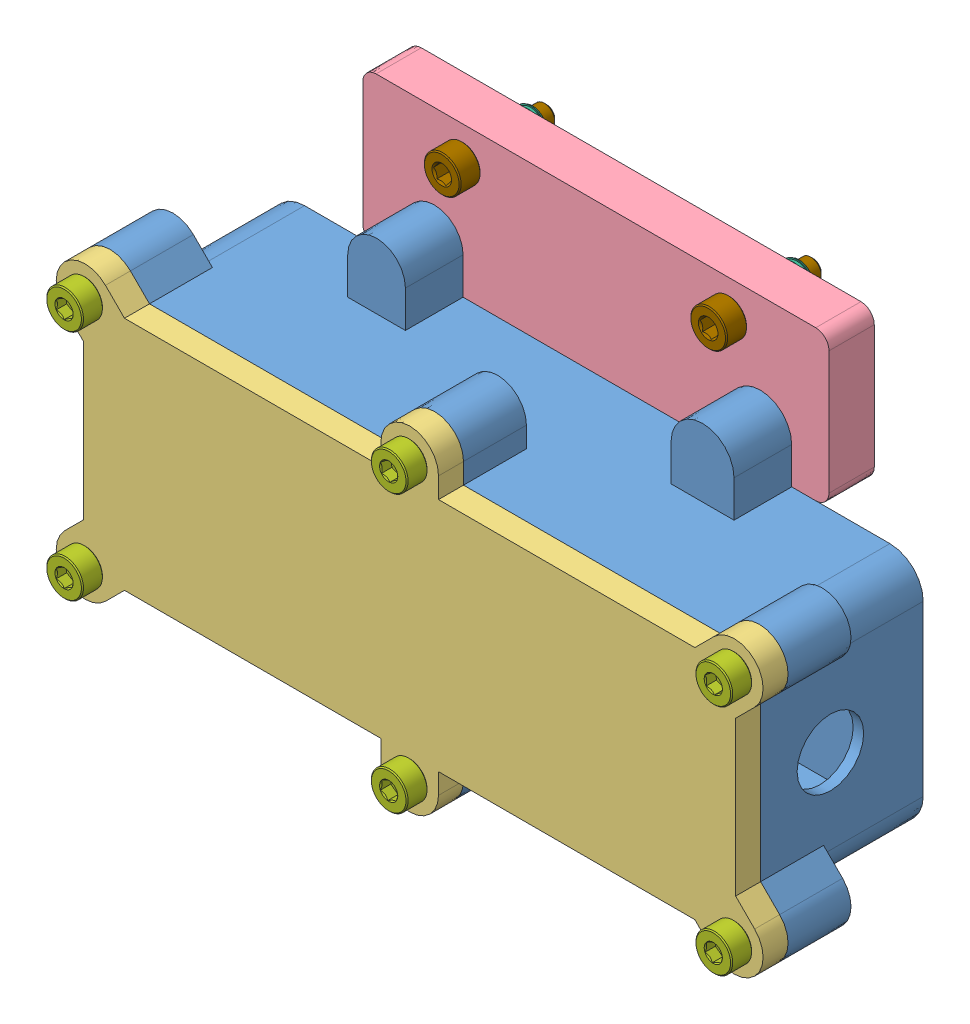
SolidWorks assembly EL-A0107-AA-HVI Assembly, configuration Default. Lengths in mm.
Overall size (134.78 82.91 55.94).
30 component instances, 9 part files, 50 mates.
Components (placement in the parent):
- EL-50090-AA-HVI Enclosure-1: EL-50090-AA-HVI Enclosure [Default] at (62.15 22.4625 5) size (134.78 67.33 31)
- EL-80091-AA-HVI PCB-1: EL-80091-AA-HVI PCB [Default] at (128.7615 -37.799 12.4115) x (0 1 0) z (0 0 1) size (31.42 97.92 12)
- EL-60092-AA-HVI Enclosure Lid-1: EL-60092-AA-HVI Enclosure Lid [Default] at (-49.5888 88.2769 31) size (134.78 63.74 4.76)
- EL-50093-AA-HVI Mounting Adapter-1: EL-50093-AA-HVI Mounting Adapter [Default] at (0 44.925 0) size (88.9 28.57 8.62)
- AC-Heat Set Insert, M4x7-4.7 (94180A351)-1: AC-Heat Set Insert, M4x7-4.7 (94180A351) [94180A351] at (0.2622 0.2622 28.65) size (6.35 6.35 4.7)
- AC-Heat Set Insert, M4x7-4.7 (94180A351)-5: AC-Heat Set Insert, M4x7-4.7 (94180A351) [94180A351] at (62.15 -3.9097 28.65) x (-0.587416 -0.809285 0) z (0 0 1) size (6.35 6.35 4.7)
- AC-Heat Set Insert, M4x7-4.7 (94180A351)-7: AC-Heat Set Insert, M4x7-4.7 (94180A351) [94180A351] at (124.0378 0.2622 28.65) x (-0.503998 -0.863705 0) z (0 0 1) size (6.35 6.35 4.7)
- FS-Heat Set Insert, M4x7-4.7 (94180A351)-7: FS-Heat Set Insert, M4x7-4.7 (94180A351) [94180A351] at (93.225 51.925 2.35) x (-0.503998 0.863705 0) z (0 0 -1) size (6.35 6.35 4.7)
- BR-Black Oxide C12.9 SHCS, M4x0.7-8 (91290A140)-7: BR-Black Oxide C12.9 SHCS, M4x0.7-8 (91290A140) [91290A140] at (93.225 51.925 -1.62) x (0.720828 -0.693114 0) z (0 0 -1) size (7 7 12.17)
- FS-Heat Set Insert, M4x7-4.7 (94180A351)-11: FS-Heat Set Insert, M4x7-4.7 (94180A351) [94180A351] at (17.6365 32.94 9.65) size (6.35 6.35 4.7)
- FS-Heat Set Insert, M4x7-4.7 (94180A351)-12: FS-Heat Set Insert, M4x7-4.7 (94180A351) [94180A351] at (17.6365 11.985 9.65) size (6.35 6.35 4.7)
- FS-Heat Set Insert, M4x7-4.7 (94180A351)-13: FS-Heat Set Insert, M4x7-4.7 (94180A351) [94180A351] at (106.2765 22.365 9.65) size (6.35 6.35 4.7)
- BR-Black Oxide C12.9 SHCS, M4x0.7-5 (91290A138)-1: BR-Black Oxide C12.9 SHCS, M4x0.7-5 (91290A138) [91290A138] at (17.6365 32.94 11.9115) x (-0.76758 0.640953 0) z (0 0 1) size (7 7 9.17)
- BR-Black Oxide C12.9 SHCS, M4x0.7-5 (91290A138)-2: BR-Black Oxide C12.9 SHCS, M4x0.7-5 (91290A138) [91290A138] at (17.6365 11.985 11.9115) x (0.49038 0.871509 0) z (0 0 1) size (7 7 9.17)
- BR-Black Oxide C12.9 SHCS, M4x0.7-5 (91290A138)-3: BR-Black Oxide C12.9 SHCS, M4x0.7-5 (91290A138) [91290A138] at (106.2765 22.365 11.9115) x (-0.851115 -0.52498 0) z (0 0 1) size (7 7 9.17) (hidden)
- 91290A154_Alloy Steel Socket Head Screw, M4x0.7, 16mm-1: 91290A154_Alloy Steel Socket Head Screw, M4x0.7, 16mm [91290A154] at (36.5 67.15 -6) x (0.781191 -0.624293 0) z (0 0 1) size (7 7 20.04)
- 91290A154_Alloy Steel Socket Head Screw, M4x0.7, 16mm-2: 91290A154_Alloy Steel Socket Head Screw, M4x0.7, 16mm [91290A154] at (87.3 67.15 -6) x (0.964834 0.262859 0) z (0 0 1) size (7 7 20.04)
- FS-Heat Set Insert, M4x7-4.7 (94180A351)-14: FS-Heat Set Insert, M4x7-4.7 (94180A351) [94180A351] at (36.5 67.15 -10.97) x (-0.244903 0.969548 0) z (0 0 1) size (6.35 6.35 4.7)
- FS-Heat Set Insert, M4x7-4.7 (94180A351)-15: FS-Heat Set Insert, M4x7-4.7 (94180A351) [94180A351] at (87.3 67.15 -10.97) x (0.839545 -0.543291 0) z (0 0 1) size (6.35 6.35 4.7)
- BR-Black Oxide C12.9 SHCS, M4x0.7-8 (91290A140)-9: BR-Black Oxide C12.9 SHCS, M4x0.7-8 (91290A140) [91290A140] at (0.2622 0.2622 33.7625) size (7 7 12.17)
- BR-Black Oxide C12.9 SHCS, M4x0.7-8 (91290A140)-10: BR-Black Oxide C12.9 SHCS, M4x0.7-8 (91290A140) [91290A140] at (62.15 -3.9097 33.7625) x (-0.596658 -0.802496 0) z (0 0 1) size (7 7 12.17)
- BR-Black Oxide C12.9 SHCS, M4x0.7-8 (91290A140)-11: BR-Black Oxide C12.9 SHCS, M4x0.7-8 (91290A140) [91290A140] at (124.0378 0.2622 33.7625) x (-0.596658 -0.802496 0) z (0 0 1) size (7 7 12.17)
- AC-Heat Set Insert, M4x7-4.7 (94180A351)-4: AC-Heat Set Insert, M4x7-4.7 (94180A351) [94180A351] at (0.2622 44.6628 28.65) x (1 0 0) z (0 0 -1) size (6.35 6.35 4.7)
- AC-Heat Set Insert, M4x7-4.7 (94180A351)-6: AC-Heat Set Insert, M4x7-4.7 (94180A351) [94180A351] at (62.15 48.8347 28.65) x (-0.587416 0.809285 0) z (0 0 -1) size (6.35 6.35 4.7)
- AC-Heat Set Insert, M4x7-4.7 (94180A351)-8: AC-Heat Set Insert, M4x7-4.7 (94180A351) [94180A351] at (124.0378 44.6628 28.65) x (-0.503998 0.863705 0) z (0 0 -1) size (6.35 6.35 4.7)
- BR-Black Oxide C12.9 SHCS, M4x0.7-8 (91290A140)-8: BR-Black Oxide C12.9 SHCS, M4x0.7-8 (91290A140) [91290A140] at (31.075 51.925 -1.62) x (0.720828 -0.693114 0) z (0 0 -1) size (7 7 12.17)
- FS-Heat Set Insert, M4x7-4.7 (94180A351)-9: FS-Heat Set Insert, M4x7-4.7 (94180A351) [94180A351] at (31.075 51.925 2.35) x (-0.503998 0.863705 0) z (0 0 -1) size (6.35 6.35 4.7) (suppressed, hidden)
- BR-Black Oxide C12.9 SHCS, M4x0.7-8 (91290A140)-12: BR-Black Oxide C12.9 SHCS, M4x0.7-8 (91290A140) [91290A140] at (0.2622 44.6628 33.7625) x (-1 0 0) z (0 0 1) size (7 7 12.17)
- BR-Black Oxide C12.9 SHCS, M4x0.7-8 (91290A140)-13: BR-Black Oxide C12.9 SHCS, M4x0.7-8 (91290A140) [91290A140] at (62.15 48.8347 33.7625) x (0.596658 -0.802496 0) z (0 0 1) size (7 7 12.17)
- BR-Black Oxide C12.9 SHCS, M4x0.7-8 (91290A140)-14: BR-Black Oxide C12.9 SHCS, M4x0.7-8 (91290A140) [91290A140] at (124.0378 44.6628 33.7625) x (0.596658 -0.802496 0) z (0 0 1) size (7 7 12.17)
Mates (geometry in assembly coordinates):
- Coincident1: coincident anti-aligned: plane of EL-500XX-AA-HVI Enclosure-1 through (62.15 22.4625 0) normal (0 0 -1)
- Coincident2: coincident anti-aligned: plane of EL-500XX-AA-HVI Enclosure-1 through (5 0 31) normal (0 -1 0)
- Coincident3: coincident anti-aligned: plane of EL-500XX-AA-HVI Enclosure-1 through (0 39.925 31) normal (-1 0 0)
- Width3: width aligned: plane of EL-500XX-AA-HVI Enclosure-1 through (5 39.925 31) normal (0 -1 0); plane of EL-800XX-BA-HVI Board-1 through (5 5 31) normal (0 1 0); plane of EL-500XX-AA-HVI Enclosure-1 through (13.1915 8.302 12) normal (0 -1 0); plane of EL-800XX-BA-HVI Board-1 through (111.1085 36.623 12) normal (0 1 0)
- Coincident5: coincident anti-aligned: plane of EL-500XX-AA-HVI Enclosure-1 through (17.6365 11.985 12) normal (0 0 1); plane of EL-800XX-BA-HVI Board-1 through (62.15 22.4625 12) normal (0 0 -1)
- Width4: width aligned: plane of EL-800XX-BA-HVI Board-1 through (111.1085 8.302 12) normal (1 0 0); plane of EL-500XX-AA-HVI Enclosure-1 through (13.1915 36.623 12) normal (-1 0 0); plane of EL-800XX-BA-HVI Board-1 through (5 39.925 31) normal (1 0 0); plane of EL-500XX-AA-HVI Enclosure-1 through (119.3 39.925 31) normal (-1 0 0)
- Coincident6: coincident aligned: plane of EL-500XX-AA-HVI Enclosure-1 through (62.15 22.4625 31) normal (0 0 1); plane of EL-60092-AA-HVI Enclosure Lid-1 through (-49.5888 88.2769 31) normal (0 0 1)
- Concentric2: concentric anti-aligned: cylinder of EL-500XX-AA-HVI Enclosure-1 through (31.075 51.925 9) axis (0 0 -1) radius 3.025; cylinder of EL-300XX-AA-HVI Enclosure Tab-2 through (31.075 51.925 0) axis (0 0 1) radius 2.25
- Coincident10: coincident anti-aligned: plane of EL-500XX-AA-HVI Enclosure-1 through (62.15 22.4625 0) normal (0 0 -1); plane of EL-300XX-AA-HVI Enclosure Tab-2 through (31.075 51.925 0) normal (0 0 1)
- Concentric4: concentric aligned: cylinder of EL-500XX-AA-HVI Enclosure-1 through (0.2622 0.2622 22) axis (0 0 1) radius 3.025; cylinder of FS-Heat Set Insert, M4x7-4.7 (94180A351)-1 through (0.2622 0.2622 31) axis (0 0 1) radius 2
- Coincident15: coincident aligned: plane of EL-500XX-AA-HVI Enclosure-1 through (62.15 22.4625 31) normal (0 0 1); plane of FS-Heat Set Insert, M4x7-4.7 (94180A351)-1 through (0.2622 2.2622 31) normal (0 0 1)
- Concentric6: concentric aligned: cylinder of EL-500XX-AA-HVI Enclosure-1 through (62.15 -3.9097 22) axis (0 0 1) radius 3.025; cylinder of AC-Heat Set Insert, M4x7-4.7 (94180A351)-5 through (62.15 -3.9097 31) axis (0 0 1) radius 2
- Coincident16: coincident aligned: plane of EL-500XX-AA-HVI Enclosure-1 through (62.15 22.4625 31) normal (0 0 1); plane of AC-Heat Set Insert, M4x7-4.7 (94180A351)-5 through (63.7686 -5.0845 31) normal (0 0 1)
- Concentric7: concentric aligned: cylinder of EL-500XX-AA-HVI Enclosure-1 through (124.0378 0.2622 22) axis (0 0 1) radius 3.025; cylinder of FS-Heat Set Insert, M4x7-4.7 (94180A351)-3 through (124.0378 0.2622 31) axis (0 0 1) radius 2
- Coincident17: coincident aligned: plane of EL-500XX-AA-HVI Enclosure-1 through (62.15 22.4625 31) normal (0 0 1); plane of FS-Heat Set Insert, M4x7-4.7 (94180A351)-3 through (125.7652 -0.7458 31) normal (0 0 1)
- Concentric16: concentric aligned: cylinder of EL-500XX-AA-HVI Enclosure-1 through (93.225 51.925 9) axis (0 0 -1) radius 3.025; cylinder of FS-Heat Set Insert, M4x7-4.7 (94180A351)-7 through (93.225 51.925 0) axis (0 0 -1) radius 2
- Coincident21: coincident aligned: plane of EL-500XX-AA-HVI Enclosure-1 through (62.15 22.4625 0) normal (0 0 -1); plane of FS-Heat Set Insert, M4x7-4.7 (94180A351)-7 through (94.9524 52.933 0) normal (0 0 -1)
- Concentric17: concentric anti-aligned: cylinder of FS-Heat Set Insert, M4x7-4.7 (94180A351)-7 through (93.225 51.925 0) axis (0 0 -1) radius 2; cylinder of BR-Black Oxide C12.9 SHCS, M4x0.7-8 (91290A140)-7 through (93.225 51.925 4.38) axis (0 0 1) radius 2
- Concentric19: concentric anti-aligned: cylinder of EL-500XX-AA-HVI Enclosure-1 through (17.6365 32.94 12) axis (0 0 -1) radius 3.025; cylinder of FS-Heat Set Insert, M4x7-4.7 (94180A351)-11 through (17.6365 32.94 12) axis (0 0 1) radius 2
- Coincident25: coincident aligned: plane of EL-500XX-AA-HVI Enclosure-1 through (17.6365 32.94 12) normal (0 0 1); plane of FS-Heat Set Insert, M4x7-4.7 (94180A351)-11 through (17.6365 34.94 12) normal (0 0 1)
- Concentric21: concentric anti-aligned: cylinder of EL-500XX-AA-HVI Enclosure-1 through (17.6365 11.985 12) axis (0 0 -1) radius 3.025; cylinder of FS-Heat Set Insert, M4x7-4.7 (94180A351)-12 through (17.6365 11.985 12) axis (0 0 1) radius 2
- Coincident26: coincident aligned: plane of EL-500XX-AA-HVI Enclosure-1 through (17.6365 11.985 12) normal (0 0 1); plane of FS-Heat Set Insert, M4x7-4.7 (94180A351)-12 through (17.6365 13.985 12) normal (0 0 1)
- Concentric22: concentric anti-aligned: cylinder of EL-500XX-AA-HVI Enclosure-1 through (106.2765 22.365 12) axis (0 0 -1) radius 3.025; cylinder of FS-Heat Set Insert, M4x7-4.7 (94180A351)-13 through (106.2765 22.365 12) axis (0 0 1) radius 2
- Coincident28: coincident aligned: plane of EL-500XX-AA-HVI Enclosure-1 through (106.2765 22.365 12) normal (0 0 1); plane of FS-Heat Set Insert, M4x7-4.7 (94180A351)-13 through (106.2765 24.365 12) normal (0 0 1)
- Concentric23: concentric anti-aligned: cylinder of FS-Heat Set Insert, M4x7-4.7 (94180A351)-11 through (17.6365 32.94 12) axis (0 0 1) radius 2; cylinder of BR-Black Oxide C12.9 SHCS, M4x0.7-5 (91290A138)-1 through (17.6365 32.94 7.4115) axis (0 0 -1) radius 2
- Coincident29: coincident anti-aligned: plane of EL-800XX-BA-HVI Board-1 through (62.15 22.4625 12.4115) normal (0 0 1); plane of BR-Black Oxide C12.9 SHCS, M4x0.7-5 (91290A138)-1 through (15.5214 30.407 12.4115) normal (0 0 -1)
- Concentric25: concentric anti-aligned: cylinder of FS-Heat Set Insert, M4x7-4.7 (94180A351)-12 through (17.6365 11.985 12) axis (0 0 1) radius 2; cylinder of BR-Black Oxide C12.9 SHCS, M4x0.7-5 (91290A138)-2 through (17.6365 11.985 7.4115) axis (0 0 -1) radius 2
- Coincident30: coincident anti-aligned: plane of EL-800XX-BA-HVI Board-1 through (62.15 22.4625 12.4115) normal (0 0 1); plane of BR-Black Oxide C12.9 SHCS, M4x0.7-5 (91290A138)-2 through (14.7605 13.6033 12.4115) normal (0 0 -1)
- Concentric26: concentric anti-aligned: cylinder of FS-Heat Set Insert, M4x7-4.7 (94180A351)-13 through (106.2765 22.365 12) axis (0 0 1) radius 2; cylinder of BR-Black Oxide C12.9 SHCS, M4x0.7-5 (91290A138)-3 through (106.2765 22.365 7.4115) axis (0 0 -1) radius 2
- Coincident32: coincident anti-aligned: plane of EL-800XX-BA-HVI Board-1 through (62.15 22.4625 12.4115) normal (0 0 1); plane of BR-Black Oxide C12.9 SHCS, M4x0.7-5 (91290A138)-3 through (108.0089 19.5563 12.4115) normal (0 0 -1)
- Coincident33: coincident anti-aligned: plane of EL-500XX-AA-HVI Enclosure-1 through (62.15 22.4625 0) normal (0 0 -1); plane of EL-50093-AA-HVI Mounting Adapter-1 through (0 44.925 0) normal (0 0 1)
- Coincident34: coincident aligned: plane of EL-500XX-AA-HVI Enclosure-1 through (5 44.925 31) normal (0 1 0); plane of EL-50093-AA-HVI Mounting Adapter-1 through (0 44.925 0) normal (0 1 0)
- Coincident35: coincident anti-aligned: plane of EL-500XX-AA-HVI Enclosure-1 through (0 39.925 31) normal (-1 0 0); plane of EL-50093-AA-HVI Mounting Adapter-1 through (0 44.925 0) normal (1 0 0)
- Coincident36: coincident anti-aligned: plane of EL-50093-AA-HVI Mounting Adapter-1 through (95.475 51.925 -3.62) normal (0 0 -1); plane of BR-Black Oxide C12.9 SHCS, M4x0.7-8 (91290A140)-7 through (90.9377 49.5463 -3.62) normal (0 0 1)
- Concentric28: concentric anti-aligned: cylinder of EL-50093-AA-HVI Mounting Adapter-1 through (36.5 67.15 0) axis (0 0 1) radius 2.25; cylinder of 91290A154_Alloy Steel Socket Head Screw, M4x0.7, 16mm-1 through (36.5 67.15 -16) axis (0 0 -1) radius 2
- Concentric29: concentric anti-aligned: cylinder of EL-50093-AA-HVI Mounting Adapter-1 through (87.3 67.15 0) axis (0 0 1) radius 2.25; cylinder of 91290A154_Alloy Steel Socket Head Screw, M4x0.7, 16mm-2 through (87.3 67.15 -16) axis (0 0 -1) radius 2
- Coincident37: coincident anti-aligned: plane of EL-50093-AA-HVI Mounting Adapter-1 through (0 44.925 0) normal (0 0 1); plane of 91290A154_Alloy Steel Socket Head Screw, M4x0.7, 16mm-1 through (38.5602 69.7279 0) normal (0 0 -1)
- Coincident38: coincident anti-aligned: plane of EL-50093-AA-HVI Mounting Adapter-1 through (0 44.925 0) normal (0 0 1); plane of 91290A154_Alloy Steel Socket Head Screw, M4x0.7, 16mm-2 through (86.4326 70.334 0) normal (0 0 -1)
- Concentric30: concentric anti-aligned: cylinder of 91290A154_Alloy Steel Socket Head Screw, M4x0.7, 16mm-2 through (87.3 67.15 -16) axis (0 0 -1) radius 2; cylinder of FS-Heat Set Insert, M4x7-4.7 (94180A351)-15 through (87.3 67.15 -8.62) axis (0 0 1) radius 2
- Coincident39: coincident anti-aligned: plane of EL-50093-AA-HVI Mounting Adapter-1 through (0 44.925 -8.62) normal (0 0 -1); plane of FS-Heat Set Insert, M4x7-4.7 (94180A351)-15 through (88.3866 68.8291 -8.62) normal (0 0 1)
- Concentric31: concentric anti-aligned: cylinder of 91290A154_Alloy Steel Socket Head Screw, M4x0.7, 16mm-1 through (36.5 67.15 -16) axis (0 0 -1) radius 2; cylinder of FS-Heat Set Insert, M4x7-4.7 (94180A351)-14 through (36.5 67.15 -8.62) axis (0 0 1) radius 2
- Coincident40: coincident anti-aligned: plane of EL-50093-AA-HVI Mounting Adapter-1 through (0 44.925 -8.62) normal (0 0 -1); circle of FS-Heat Set Insert, M4x7-4.7 (94180A351)-14
- Coincident41: coincident aligned: plane of EL-50090-AA-HVI Enclosure-1 through (0 39.925 31) normal (-1 0 0); plane of EL-600XX-AA-HVI Enclosure Lid-1 through (0 37.1468 35.7625) normal (-1 0 0)
- Coincident42: coincident aligned: plane of EL-50090-AA-HVI Enclosure-1 through (5 0 31) normal (0 -1 0); plane of EL-600XX-AA-HVI Enclosure Lid-1 through (7.7782 0 35.7625) normal (0 -1 0)
- Concentric32: concentric anti-aligned: cylinder of AC-Heat Set Insert, M4x7-4.7 (94180A351)-1 through (0.2622 0.2622 31) axis (0 0 1) radius 2; cylinder of BR-Black Oxide C12.9 SHCS, M4x0.7-8 (91290A140)-9 through (0.2622 0.2622 27.7625) axis (0 0 -1) radius 2
- Coincident43: coincident anti-aligned: plane of EL-60092-AA-HVI Enclosure Lid-1 through (62.15 48.8347 35.7625) normal (0 0 1); plane of BR-Black Oxide C12.9 SHCS, M4x0.7-8 (91290A140)-9 through (0.2622 3.5622 35.7625) normal (0 0 -1)
- Concentric33: concentric anti-aligned: cylinder of AC-Heat Set Insert, M4x7-4.7 (94180A351)-5 through (62.15 -3.9097 31) axis (0 0 1) radius 2; cylinder of BR-Black Oxide C12.9 SHCS, M4x0.7-8 (91290A140)-10 through (62.15 -3.9097 27.7625) axis (0 0 -1) radius 2
- Coincident45: coincident anti-aligned: plane of EL-60092-AA-HVI Enclosure Lid-1 through (62.15 48.8347 35.7625) normal (0 0 1); plane of BR-Black Oxide C12.9 SHCS, M4x0.7-8 (91290A140)-10 through (64.7982 -5.8787 35.7625) normal (0 0 -1)
- Concentric34: concentric anti-aligned: cylinder of EL-60092-AA-HVI Enclosure Lid-1 through (124.0378 0.2622 35.7625) axis (0 0 1) radius 2.25; cylinder of BR-Black Oxide C12.9 SHCS, M4x0.7-8 (91290A140)-11 through (124.0378 0.2622 27.7625) axis (0 0 -1) radius 2
- Coincident46: coincident anti-aligned: plane of EL-60092-AA-HVI Enclosure Lid-1 through (62.15 48.8347 35.7625) normal (0 0 1); circle of BR-Black Oxide C12.9 SHCS, M4x0.7-8 (91290A140)-11
